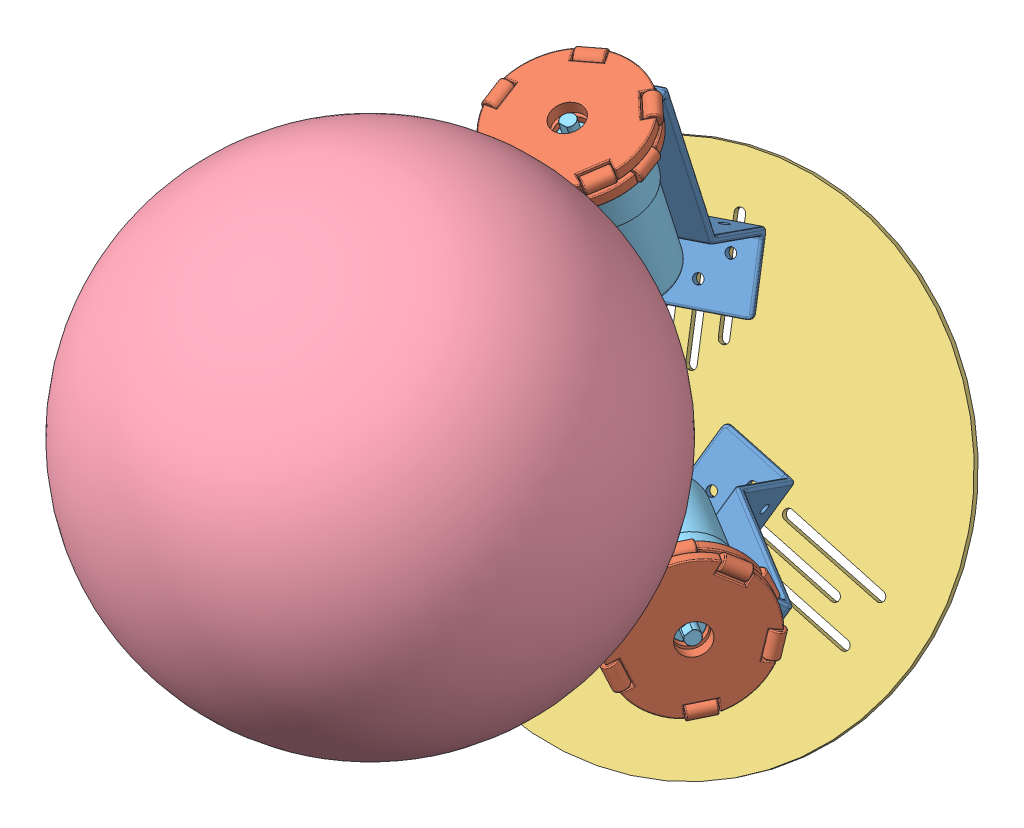
SolidWorks assembly Assembly1, configuration Default. Lengths in mm.
Overall size (255.27 312.31 350.87).
14 component instances, 5 part files, 35 mates.
Components (placement in the parent):
- FixMotorPart-1: FixMotorPart [Default] at (245.9622 -21.1968 -27.0255) x (-0.34742 0.294775 -0.890172) z (0.014884 0.950919 0.309082) size (71.58 40 121.2)
- HaftOmniWheel-1: HaftOmniWheel [Default] at (338.6084 -140.213 20.4287) x (-0.534183 -0.084297 0.841155) z (0.838441 0.074292 0.539905) size (60.44 59.16 6.4)
- FixMotorPart-2: FixMotorPart [Default] at (337.2748 -144.6271 12.9202) x (0.476137 -0.581852 -0.65935) z (0.838441 0.074292 0.539905) size (71.58 40 121.2)
- HaftOmniWheel-2: HaftOmniWheel [Default] at (204.1232 -166.9562 81.5266) x (0.504518 -0.853901 0.127728) z (0.309869 0.040995 -0.949895) size (60.44 59.16 6.4)
- FixMotorPart-3: FixMotorPart [Default] at (203.3692 -171.2429 67.9363) x (-0.672173 -0.697139 -0.249359) z (-0.309869 -0.040995 0.949895) size (71.58 40 121.2)
- HaftOmniWheel-3: HaftOmniWheel [Default] at (248.4357 -17.996 -19.1975) x (0.442029 0.271012 -0.85508) z (-0.014884 -0.950919 -0.309082) size (60.44 59.16 6.4)
- HaftOmniWheel-4: HaftOmniWheel [Default] at (206.2922 -166.6692 74.8774) x (-0.922342 -0.229556 -0.310788) z (0.309869 0.040995 -0.949895) size (60.44 59.16 6.4)
- HaftOmniWheel-5: HaftOmniWheel [Default] at (344.4775 -139.693 24.208) x (-0.36868 -0.652261 0.662292) z (0.838441 0.074292 0.539905) size (60.44 59.16 6.4)
- HaftOmniWheel-6: HaftOmniWheel [Default] at (248.5399 -11.3396 -17.034) x (-0.169562 0.30704 -0.93647) z (-0.014884 -0.950919 -0.309082) size (60.44 59.16 6.4)
- MainPart-1: MainPart [Default] at (244.8934 -168.9658 -71.5709) x (0.937591 0.094132 -0.334756) z (0.256188 0.463964 0.848001) size (203.72 203.72 3)
- Ball64cm-2: Ball64cm [Default] at (278.8474 -57.8254 101.4853) size (203.72 203.72 203.72)
- Motor-1: Motor [Default] at (244.9177 -20.1801 -30.103) x (0.34742 -0.294775 0.890172) z (-0.014884 -0.950919 -0.309082) size (37 37 81)
- Motor-2: Motor [Default] at (200.9839 -173.5097 67.0604) x (0.672173 0.697139 0.249359) z (0.309869 0.040995 -0.949895) size (37 37 81)
- Motor-3: Motor [Default] at (338.8558 -146.7254 10.7537) x (-0.476137 0.581852 0.65935) z (-0.838441 -0.074292 -0.539905) size (37 37 81)
Mates (geometry in assembly coordinates):
- Concentric1: concentric aligned: cylinder of HaftOmniWheel-3 through (248.3985 -20.3733 -19.9703) axis (0.014884 0.950919 0.309082) radius 6.5; cylinder of HaftOmniWheel-6 through (248.5027 -13.7169 -17.8067) axis (0.014884 0.950919 0.309082) radius 6.5
- Distance1: distance = 2 mm anti-aligned: plane of HaftOmniWheel-3 through (248.473 -15.6187 -18.4248) normal (0.014884 0.950919 0.309082); plane of HaftOmniWheel-6 through (248.5027 -13.7169 -17.8067) normal (-0.014884 -0.950919 -0.309082)
- Angle1: planar angle = 0.628319 rad anti-aligned: plane of HaftOmniWheel-6 through (250.462 -18.8744 6.0551) normal (0.989575 -0.058293 0.131691); plane of HaftOmniWheel-3 through (256.2318 -26.2561 5.84) normal (-0.88478 -0.131468 0.44708)
- Concentric2: concentric anti-aligned: cylinder of HaftOmniWheel-2 through (204.8978 -166.8537 79.1519) axis (-0.309869 -0.040995 0.949895) radius 6.5; circle of HaftOmniWheel-4
- Distance4: distance = 2 mm anti-aligned: plane of HaftOmniWheel-4 through (205.5176 -166.7717 77.2521) normal (-0.309869 -0.040995 0.949895); plane of HaftOmniWheel-2 through (204.8978 -166.8537 79.1519) normal (0.309869 0.040995 -0.949895)
- Angle2: planar angle = 0.628319 rad anti-aligned: plane of HaftOmniWheel-4 through (192.2594 -147.1061 71.1439) normal (0.610533 0.757296 0.231848); plane of HaftOmniWheel-2 through (181.2323 -170.3627 73.9123) normal (-0.06552 -0.995774 -0.064349)
- Concentric3: concentric anti-aligned: circle of HaftOmniWheel-1; cylinder of HaftOmniWheel-5 through (346.5736 -139.5073 25.5578) axis (-0.838441 -0.074292 -0.539905) radius 6.5
- Distance5: distance = 2 mm anti-aligned: plane of HaftOmniWheel-1 through (340.7045 -140.0273 21.7785) normal (0.838441 0.074292 0.539905); plane of HaftOmniWheel-5 through (342.3814 -139.8787 22.8583) normal (-0.838441 -0.074292 -0.539905)
- Angle3: planar angle = 0.628319 rad anti-aligned: plane of HaftOmniWheel-5 through (333.1211 -155.0792 43.9611) normal (0.267789 -0.918985 -0.289407); plane of HaftOmniWheel-1 through (329.8312 -160.4468 36.8435) normal (-0.495646 0.515865 0.698726)
- Distance6: distance = 0 mm anti-aligned: plane of MainPart-1 through (245.662 -167.5739 -69.0269) normal (0.256188 0.463964 0.848001); plane of FixMotorPart-3 through (176.8262 -219.3131 -19.9232) normal (-0.256188 -0.463964 -0.848001)
- Parallel2: parallel anti-aligned: plane of FixMotorPart-2 through (310.7317 -192.6974 -74.9393) normal (-0.256188 -0.463964 -0.848001); plane of MainPart-1 through (245.662 -167.5739 -69.0269) normal (0.256188 0.463964 0.848001)
- Distance7: distance = 0 mm anti-aligned: plane of MainPart-1 through (245.662 -167.5739 -69.0269) normal (0.256188 0.463964 0.848001); plane of FixMotorPart-2 through (310.7317 -192.6974 -74.9393) normal (-0.256188 -0.463964 -0.848001)
- Parallel3: parallel anti-aligned: plane of FixMotorPart-1 through (219.4191 -69.2671 -114.885) normal (-0.256188 -0.463964 -0.848001); plane of MainPart-1 through (245.662 -167.5739 -69.0269) normal (0.256188 0.463964 0.848001)
- Distance8: distance = 0 mm anti-aligned: plane of MainPart-1 through (245.662 -167.5739 -69.0269) normal (0.256188 0.463964 0.848001); plane of FixMotorPart-1 through (219.4191 -69.2671 -114.885) normal (-0.256188 -0.463964 -0.848001)
- Parallel4: parallel anti-aligned: plane of FixMotorPart-1 through (264.7587 -16.4614 -32.7934) normal (0.937591 0.094132 -0.334756); plane of MainPart-1 through (247.5372 -167.3857 -69.6964) normal (-0.937591 -0.094132 0.334756)
- Distance9: distance = 22 mm aligned: plane of FixMotorPart-1 through (264.7587 -16.4614 -32.7934) normal (0.937591 0.094132 -0.334756); plane of MainPart-1 through (243.7868 -167.7622 -68.3574) normal (0.937591 0.094132 -0.334756)
- Parallel5: parallel aligned: plane of FixMotorPart-2 through (334.4869 -160.6021 25.0044) normal (-0.26516 -0.809895 0.523222); plane of MainPart-1 through (243.5407 -174.0531 -64.8412) normal (-0.26516 -0.809895 0.523222)
- Distance11: distance = 22 mm aligned: plane of FixMotorPart-2 through (334.4869 -160.6021 25.0044) normal (-0.26516 -0.809895 0.523222); plane of MainPart-1 through (246.1923 -165.9541 -70.0734) normal (-0.26516 -0.809895 0.523222)
- Distance13: distance = 22 mm aligned: plane of FixMotorPart-3 through (215.8883 -185.6811 74.5553) normal (0.672431 -0.715763 0.188466); plane of MainPart-1 through (244.3171 -166.1424 -69.4039) normal (0.672431 -0.715763 0.188466)
- Concentric14: concentric anti-aligned: cylinder of FixMotorPart-1 through (248.3985 -20.3733 -19.9703) axis (-0.014884 -0.950919 -0.309082) radius 6.207; cylinder of HaftOmniWheel-6 through (248.5027 -13.7169 -17.8067) axis (0.014884 0.950919 0.309082) radius 6.5
- Distance16: distance = 0 mm anti-aligned: plane of HaftOmniWheel-3 through (248.3985 -20.3733 -19.9703) normal (-0.014884 -0.950919 -0.309082); plane of FixMotorPart-1 through (246.0069 -18.344 -26.0983) normal (0.014884 0.950919 0.309082)
- Concentric15: concentric anti-aligned: cylinder of HaftOmniWheel-2 through (204.8978 -166.8537 79.1519) axis (-0.309869 -0.040995 0.949895) radius 6.5; cylinder of FixMotorPart-3 through (207.0669 -166.5667 72.5026) axis (0.309869 0.040995 -0.949895) radius 6.207
- Distance17: distance = 0 mm anti-aligned: plane of HaftOmniWheel-4 through (207.0669 -166.5667 72.5026) normal (0.309869 0.040995 -0.949895); plane of FixMotorPart-3 through (202.4396 -171.3659 70.786) normal (-0.309869 -0.040995 0.949895)
- Concentric16: concentric aligned: cylinder of FixMotorPart-2 through (336.5123 -140.3988 19.0789) axis (-0.838441 -0.074292 -0.539905) radius 6.207; cylinder of HaftOmniWheel-5 through (346.5736 -139.5073 25.5578) axis (-0.838441 -0.074292 -0.539905) radius 6.5
- Distance18: distance = 0 mm anti-aligned: plane of HaftOmniWheel-1 through (336.5123 -140.3988 19.0789) normal (-0.838441 -0.074292 -0.539905); plane of FixMotorPart-2 through (339.7901 -144.4043 14.5399) normal (0.838441 0.074292 0.539905)
- Concentric18: concentric aligned: cylinder of FixMotorPart-1 through (248.3985 -20.3733 -19.9703) axis (-0.014884 -0.950919 -0.309082) radius 6.207; cylinder of Motor-1 through (248.4432 -17.5205 -19.043) axis (-0.014884 -0.950919 -0.309082) radius 6.207
- Distance20: distance = 0 mm anti-aligned: plane of Motor-1 through (245.9011 -21.1782 -27.0796) normal (0.014884 0.950919 0.309082); plane of FixMotorPart-1 through (245.9622 -21.1968 -27.0255) normal (-0.014884 -0.950919 -0.309082)
- Concentric20: concentric aligned: cylinder of FixMotorPart-2 through (336.5123 -140.3988 19.0789) axis (-0.838441 -0.074292 -0.539905) radius 6.207; cylinder of Motor-3 through (339.0277 -140.1759 20.6987) axis (-0.838441 -0.074292 -0.539905) radius 6.207
- Concentric21: concentric anti-aligned: cylinder of FixMotorPart-1 through (234.7601 -14.8882 -36.1887) axis (-0.014884 -0.950919 -0.309082) radius 2; cylinder of Motor-1 through (234.6708 -20.5938 -38.0432) axis (0.014884 0.950919 0.309082) radius 2
- Concentric22: concentric anti-aligned: cylinder of FixMotorPart-1 through (260.865 -17.1916 -30.3595) axis (-0.014884 -0.950919 -0.309082) radius 2; cylinder of Motor-1 through (260.7757 -22.8971 -32.214) axis (0.014884 0.950919 0.309082) radius 2
- Concentric23: concentric anti-aligned: cylinder of FixMotorPart-2 through (344.381 -132.4774 5.7694) axis (-0.838441 -0.074292 -0.539905) radius 2; cylinder of Motor-3 through (339.3503 -132.9231 2.53) axis (0.838441 0.074292 0.539905) radius 2
- Distance22: distance = 0 mm anti-aligned: plane of Motor-3 through (337.3204 -144.6404 12.8512) normal (0.838441 0.074292 0.539905); plane of FixMotorPart-2 through (337.2748 -144.6271 12.9202) normal (-0.838441 -0.074292 -0.539905)
- Concentric24: concentric aligned: cylinder of FixMotorPart-3 through (207.0669 -166.5667 72.5026) axis (0.309869 0.040995 -0.949895) radius 6.207; cylinder of Motor-2 through (206.1373 -166.6897 75.3523) axis (0.309869 0.040995 -0.949895) radius 6.207
- Concentric25: concentric anti-aligned: cylinder of FixMotorPart-3 through (212.1476 -183.1531 73.4442) axis (0.309869 0.040995 -0.949895) radius 2; cylinder of Motor-2 through (214.0068 -182.9071 67.7448) axis (-0.309869 -0.040995 0.949895) radius 2
- Distance23: distance = 0 mm anti-aligned: plane of FixMotorPart-3 through (203.3692 -171.2429 67.9363) normal (0.309869 0.040995 -0.949895); plane of Motor-2 through (203.3441 -171.3219 67.9247) normal (-0.309869 -0.040995 0.949895)
